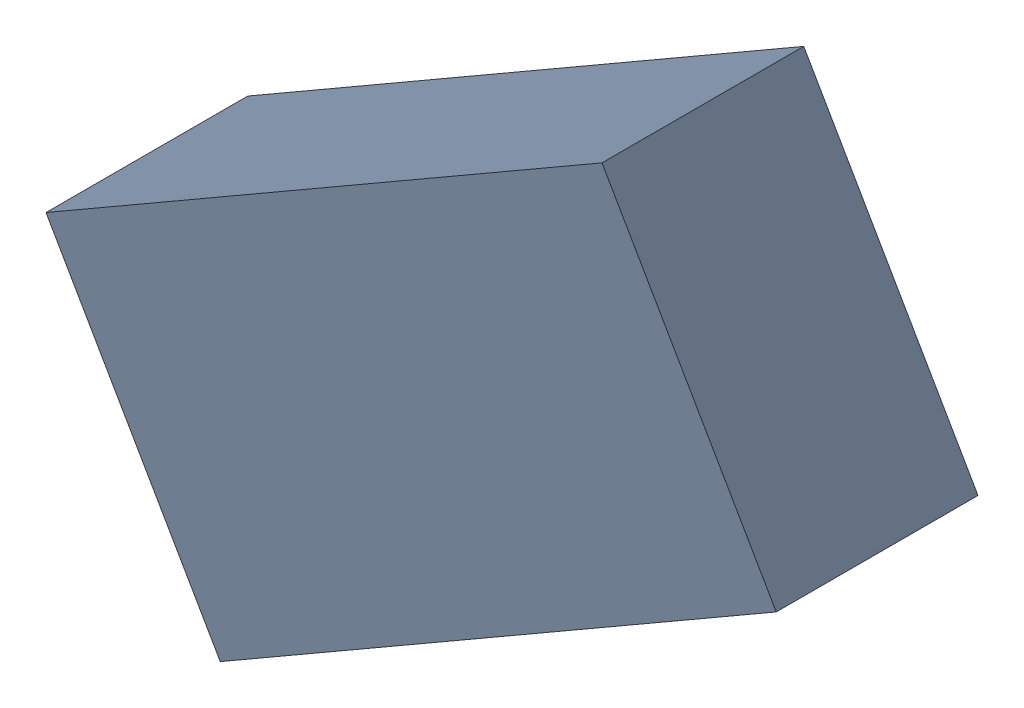
SolidWorks assembly L3_TDA2, configuration Standard. Lengths in mm.
Overall size (1.99 1.7 0.55).
2 component instances, 1 part files, 0 mates.
Components (placement in the parent):
- 885543736-1: 885543736 [Standard] at (50.8702 28.6654 0) size (1.99 1.7 0.55)
  - Extruded_21-1: Extruded_21 [Standard] at origin size (1.99 1.7 0.55)
